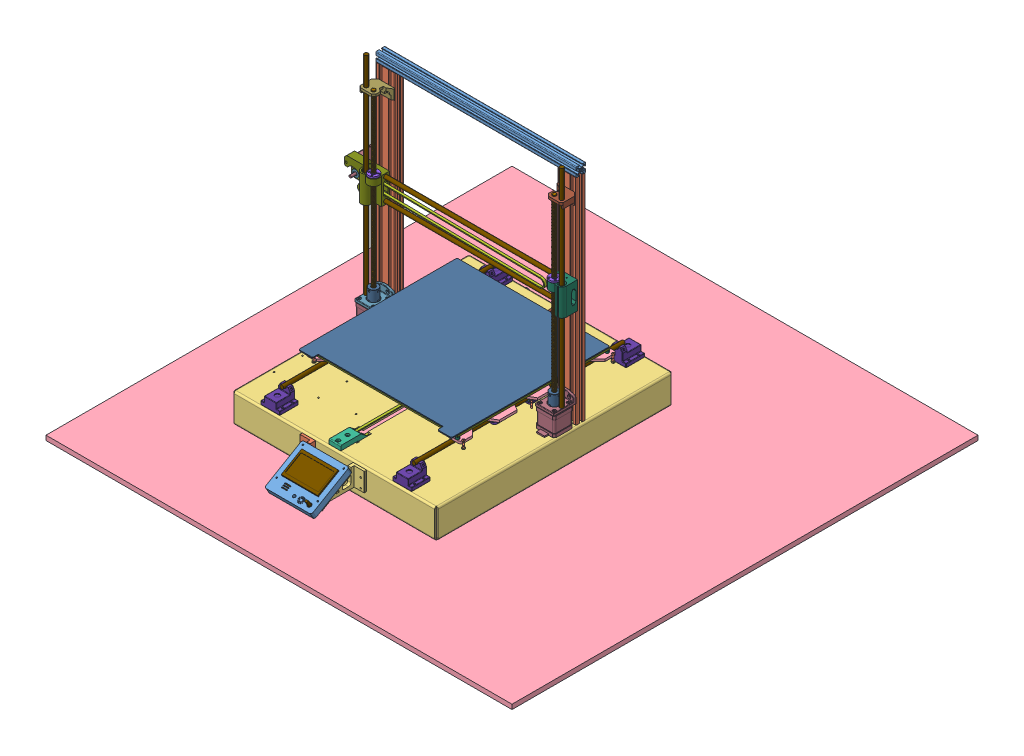
SolidWorks assembly Complete Assembly, configuration Default. Lengths in mm.
Overall size (1000 587.54 1000).
95 component instances, 40 part files, 24 mates.
Components (placement in the parent):
- Frame Assembly-1: Frame Assembly [Default] at (-40.4622 11.3616 41.4357) size (437.82 543.39 517.28)
  - Frame and Cover-1: Frame and Cover [Default] at (488.7599 -20.5544 105.3834) size (437.82 543.39 507.82)
    - TopCeiling-1: TopCeiling [20-2020-BLACK] at (-74.5195 587.4544 205.3802) x (0 0 -1) z (1 0 0) size (20 20 430)
    - UprightSides-1: UprightSides [20-2040-BLACK] at (-84.5195 117.4544 205.3802) x (1 0 0) z (0 -1 0) size (40 20 460)
    - UprightSides-2: UprightSides [20-2040-BLACK] at (-474.5195 117.4544 205.3802) x (1 0 0) z (0 -1 0) size (40 20 460)
    - printer_Cover-1: printer_Cover [Default] at (-81.1195 117.4544 131.1302) size (437.82 62.09 507.82)
    - bottom_Cover-1: bottom_Cover [Default] at (4575.451 55.3678 5402.6088) size (430 1.3 500)
  - power switch-1: power switch [Standard] at (101.2109 67.9884 116.852) size (58.2 48.75 32.65)
  - EinsyAssembly_StandOff-1: EinsyAssembly_StandOff [Default] at (-6.2482 152.6016 450.1588) x (1 0 0) z (0 -1 0) size (108.28 71 27.59)
    - Einsy_Rambo-1: Einsy_Rambo [Default] at (14.9676 86.704 68.4713) size (108.28 71 21.5)
    - standOffs-1: standOffs [Default] at (92.9775 34.4902 66.8766) x (1 0 0) z (0 -1 0) size (5 8 5)
    - standOffs-3: standOffs [Default] at (92.6031 96.0937 66.8766) x (0 1 0) z (1 0 0) size (5 8 5)
    - standOffs-4: standOffs [Default] at (-2.0225 34.4902 66.8766) x (1 0 0) z (0 -1 0) size (5 8 5)
    - standOffs-5: standOffs [Default] at (-2.0225 95.4902 66.8766) x (1 0 0) z (0 -1 0) size (5 8 5)
  - 24V15A power supply-5: 24V15A power supply [Standard] at (78.7404 93.725 345.2636) x (0 0 -1) z (0 -1 0) size (215 113 50)
  - wireClamp_25-6: wireClamp_25 [Default] at (150.0789 96.5825 393.0636) x (-1 0 0) z (0 0 1) size (41.15 12.95 25.4)
  - wireClamp_25-7: wireClamp_25 [Default] at (150.0789 96.5825 268.0636) x (-1 0 0) z (0 0 1) size (41.15 12.95 25.4)
  - wireClamp_25-8: wireClamp_25 [Default] at (169.9404 96.5825 513.6021) x (0 0 -1) z (-1 0 0) size (41.15 12.95 25.4)
  - wireClamp_25-9: wireClamp_25 [Default] at (100.0789 96.5825 168.0636) x (-1 0 0) z (0 0 1) size (41.15 12.95 25.4)
- Y Assembly-1: Y Assembly [Default] at (145.6024 117.3436 67.5916) x (0.999825 0 0.018712) z (-0.018712 0 0.999825) size (352.33 81 500.19)
  - PrintBed_328x328-1: PrintBed_328x328 [Default] at (148.0124 43.9926 305.9077) x (0.999825 0 -0.018712) z (0.018712 0 0.999825) size (328 2 340)
  - y axis motor holder-1: y axis motor holder [Default] at (-4.3973 -9.082 94.7066) x (0 1 0) z (0.999825 0 -0.018712) size (46.75 77.5 19)
  - 624U pillow-1: 624U pillow [Standard] at (74.1469 -91.082 589.2534) x (0 1 0) z (0.018712 0 0.999825) size (13 4 13)
  - 40-42 motor-1: 40-42 motor [Standard] at (-45.9053 -85.582 96.0835) x (0 1 0) z (-0.018712 0 -0.999825) size (42 64 50.7)
  - 2GT-pulley-2: 2GT-pulley [Standard] at (-58.242 121.3888 274.0832) x (0.999825 0 -0.018712) z (0.018712 0 0.999825) size (16 15 15)
  - 5mm Bed Spacer-1: 5mm Bed Spacer [Default] at (-134.2258 34.9926 494.9836) size (7 5 7)
  - 5mm Bed Spacer-2: 5mm Bed Spacer [Default] at (186.7203 34.9926 489.0988) size (7 5 7)
  - 5mm Bed Spacer-3: 5mm Bed Spacer [Default] at (180.5919 34.398 168.1573) size (7 5 7)
  - 5mm Bed Spacer-4: 5mm Bed Spacer [Default] at (-140.2301 34.398 174.1616) size (7 5 7)
  - HeatBed 300mm-1: HeatBed 300mm [Default] at (26.2199 39.9926 264.6988) x (0.999825 0 -0.018712) z (0.018712 0 0.999825) size (327 4 327)
  - Bed Holder-3: Bed Holder [Default] at (-121.7577 30.1666 403.8738) x (0.018712 0 0.999825) z (0.999825 0 -0.018712) size (22 20 30)
  - Bed Holder-4: Bed Holder [Default] at (159.7692 30.1666 322.5141) x (0.018712 0 0.999825) z (0.999825 0 -0.018712) size (22 20 30)
  - Bed Holder-5: Bed Holder [Default] at (160.7796 30.1666 376.5016) x (-0.018712 0 -0.999825) z (-0.999825 0 0.018712) size (22 20 30)
  - Bed Holder-6: Bed Holder [Default] at (-123.593 30.1666 305.8134) x (-0.018712 0 -0.999825) z (-0.999825 0 0.018712) size (22 20 30)
  - BedSlider-1: BedSlider [Default] at (160.3516 26.2711 115.9371) x (0.404254 0.914616 -0.007566) z (0.018712 0 0.999825) size (8 8 450)
  - BedSlider-2: BedSlider [Default] at (-126.0037 27.7452 121.2964) x (-0.108153 0.994132 0.002024) z (0.018712 0 0.999825) size (8 8 450)
  - lm8uu-1: lm8uu [Default] at (159.5633 20.6666 311.516) x (0.999825 0 -0.018712) z (0.018712 0 0.999825) size (15 15 24)
  - lm8uu-2: lm8uu [Default] at (160.9854 20.6666 387.4997) x (0.999825 0 -0.018712) z (0.018712 0 0.999825) size (15 15 24)
  - lm8uu-3: lm8uu [Default] at (-121.9636 20.6666 392.8757) x (0.999825 0 -0.018712) z (0.018712 0 0.999825) size (15 15 24)
  - lm8uu-4: lm8uu [Default] at (-123.3871 20.6666 316.8115) x (0.999825 0 -0.018712) z (0.018712 0 0.999825) size (15 15 24)
  - M3X16MM-1: M3X16MM [92095A184] at (190.5681 45.048 170.847) x (0.585178 0 0.810905) z (0 1 0) size (5.7 5.7 18)
  - M3X16MM-2: M3X16MM [92095A184] at (-130.3757 45.048 176.8536) x (0.988184 0 0.153271) z (0 1 0) size (5.7 5.7 18)
  - M3X16MM-3: M3X16MM [92095A184] at (-124.3691 45.048 497.7974) x (0.998383 0 0.056849) z (0 1 0) size (5.7 5.7 18)
  - M3X16MM-4: M3X16MM [92095A184] at (196.5747 45.048 491.7908) x (0.969741 0 0.244134) z (0 1 0) size (5.7 5.7 18)
  - M3-1: M3 [90591A250] at (-130.3757 17.3906 176.8536) x (0.962335 0 -0.271866) z (0 1 0) size (5.5 6.35 2.78)
  - M3-2: M3 [90591A250] at (190.5681 28.9666 170.847) x (1 0 0) z (0 1 0) size (5.5 6.35 2.78)
  - M3-3: M3 [90591A250] at (196.5747 28.9666 491.7908) x (1 0 0) z (0 1 0) size (5.5 6.35 2.78)
  - M3-4: M3 [90591A250] at (-124.3691 28.9666 497.7974) x (0.977813 0 0.209477) z (0 -1 0) size (5.5 6.35 2.78)
  - M3X16MM-5: M3X16MM [92095A184] at (170.9836 21.7666 387.3126) x (-0.990608 0 0.136731) z (0 -1 0) size (5.7 5.7 18)
  - M3X16MM-6: M3X16MM [92095A184] at (150.939 25.0666 399.5855) x (-0.757878 0 0.652397) z (0 1 0) size (5.7 5.7 18)
  - M3X16MM-7: M3X16MM [92095A184] at (150.939 25.0666 323.5885) x (-0.527844 0 0.849341) z (0 1 0) size (5.7 5.7 18)
  - M3X16MM-8: M3X16MM [92095A184] at (170.939 25.0666 323.5885) x (-0.850892 0 0.525341) z (0 1 0) size (5.7 5.7 18)
  - M3X16MM-9: M3X16MM [92095A184] at (-127.261 25.0666 399.5855) x (-0.32634 0 -0.945252) z (0 1 0) size (5.7 5.7 18)
  - M3X16MM-10: M3X16MM [92095A184] at (-107.261 25.0666 399.5855) x (-0.992075 0 0.125643) z (0 1 0) size (5.7 5.7 18)
  - M3X16MM-11: M3X16MM [92095A184] at (-127.261 25.0666 323.5885) x (-0.951434 0 -0.307853) z (0 1 0) size (5.7 5.7 18)
  - M3X16MM-12: M3X16MM [92095A184] at (-107.261 25.871 323.5885) x (-0.671818 0 -0.740717) z (0 1 0) size (5.7 5.7 18)
  - M3X16MM-13: M3X16MM [92095A184] at (5.6078 -25.582 167.032) x (-0.018712 0 -0.999825) z (0.999825 0 -0.018712) size (5.7 5.7 18)
  - M3X16MM-14: M3X16MM [92095A184] at (5.0277 5.418 136.0374) x (-0.018712 0 -0.999825) z (0.999825 0 -0.018712) size (5.7 5.7 18)
  - flatbed-2: flatbed [Default] at (144.4975 32.5796 357.2347) x (0.999825 0 -0.018712) z (0 -1 0) size (335 335 4.83)
  - y belt holder-1: y belt holder [Default] at (10.4795 30.1666 328.4691) x (0.999825 0 -0.018712) z (0 -1 0) size (14 52 33.5)
  - Y axis Idler Holder-1: Y axis Idler Holder [Default] at (21.7058 0.918 594.3056) x (0.018712 0 0.999825) z (0 -1 0) size (56.89 25 35)
  - belt-4: belt [Default] at (16.5258 -7.7421 183.9241) x (0.01871 0.016655 0.999686) z (-0.999825 0 0.018712) size (414.43 26.57 5)
- XAssembly-1: XAssembly [Default] at (346.1628 88.2378 346.754) size (485.02 523.02 93.11)
  - 40-42 motor-1: 40-42 motor [Standard] at (83.3654 18.4973 -13.9547) x (-1 0 0) z (0 0 -1) size (42 64 50.7)
  - 40-42 motor-2: 40-42 motor [Standard] at (-304.6346 18.4973 -13.9547) x (-1 0 0) z (0 0 -1) size (42 64 50.7)
  - 624U pillow-1: 624U pillow [Standard] at (-70.3846 223.0937 -25.0811) x (1 0 0) z (0 -1 0) size (13 4 13)
  - 2GT-pulley-1: 2GT-pulley [Standard] at (-298.4371 388.8614 -49.1082) x (0 0 1) z (0 1 0) size (16 15 15)
  - flanged lead screw nut-1: flanged lead screw nut [Default] at (-380.1347 299.5237 42.4453) x (-0.892252 0 0.451538) z (0 -1 0) size (22 22 19.88)
  - flanged lead screw nut-2: flanged lead screw nut [Default] at (7.8652 299.5237 42.4453) x (0.837169 0 0.546944) z (0 -1 0) size (22 22 19.88)
  - 40-42 motor-3: 40-42 motor [Standard] at (-354.4079 323.9237 -22.4949) x (-1 0 0) z (0 1 0) size (42 64 50.7)
  - BedSlider-1: BedSlider [Default] at (-396.8878 512.0237 35.3611) x (0.113678 0 -0.993518) z (0 -1 0) size (8 8 450)
  - BedSlider-2: BedSlider [Default] at (19.3272 512.0237 36.7178) x (-0.378404 0 -0.925641) z (0 -1 0) size (8 8 450)
  - Z threaded rod-1: Z threaded rod [Standard] at (-380.1346 84.0237 42.4453) x (0 0 -1) z (0 1 0) size (8.01 8.01 375.98)
  - Z threaded rod-2: Z threaded rod [Standard] at (7.8394 454.0237 42.4545) x (-1 0 0) z (0 -1 0) size (8.01 8.01 375.98)
  - Z coupler-1: Z coupler [Standard] at (-380.1346 75.0237 42.4453) size (20 26 20)
  - Z coupler-2: Z coupler [Standard] at (7.8654 75.0237 42.4453) size (20 26 20)
  - ztop holder Right-1: ztop holder Right [Default] at (-30.6346 447.0237 42.4453) x (-1 0 0) z (0 0 -1) size (43 21 35.75)
  - ztop holder Left-1: ztop holder Left [Default] at (-380.1346 447.0237 42.4453) x (-1 0 0) z (0 0 -1) size (43 21 35.75)
  - Y motor holder right-1: Y motor holder right [Default] at (7.8654 60.0237 42.4453) size (39.5 20 48)
  - Y motor holder left-1: Y motor holder left [Default] at (-380.1346 60.0237 42.4453) size (39.5 20 48)
  - Right z holder-1: Right z holder [Default] at (15.6154 267.0237 18.9453) x (0 1 0) z (1 0 0) size (58 34.5 38.04)
  - Motor Mount-2: Motor Mount [Default] at (-369.4576 296.0237 35.9453) x (-1 0 0) z (0 0 -1) size (81.27 58 36)
  - BedSlider-3: BedSlider [Default] at (33.1119 291.8257 20.521) x (0 0 -1) z (-1 0 0) size (8 8 450)
  - BedSlider-4: BedSlider [Default] at (-420.7175 244.9609 20.2907) x (0 0.24335 -0.969938) z (1 0 0) size (8 8 450)
  - belt-1: belt [Default] at (-397.4115 269.2854 25.1733) size (414.43 26.57 5)
- Linear Holder-1: Linear Holder [Default] at (17.2782 112.2616 642.1993) x (1 0 0) z (0 0 -1) size (41 31.25 40)
- Linear Holder-2: Linear Holder [Default] at (300.2782 112.2616 642.1993) x (1 0 0) z (0 0 -1) size (41 31.25 40)
- Linear Holder-3: Linear Holder [Default] at (300.2782 112.2616 182.1993) x (-1 0 0) z (0 0 1) size (41 31.25 40)
- Linear Holder-4: Linear Holder [Default] at (17.2782 112.2616 182.1993) x (-1 0 0) z (0 0 1) size (41 31.25 40)
- Screen Assembly-1: Screen Assembly [Default] at (221.4776 20.2859 772.4029) x (1 0 0) z (0 0.863792 0.503849) size (138.95 107.39 82.56)
  - Full Graphic Smart Controller-2: Full Graphic Smart Controller [Default] at (-62.6096 73.8061 19.9222) size (102.9 86.75 34.7)
  - LCD_Case-2: LCD_Case [Default] at (-68.3227 84.8365 18.8222) size (100.75 94 14)
  - LCD_Holder_Left-1: LCD_Holder_Left [Default] at (-103.0846 92.3537 17.2607) x (1 0 0) z (0 -0.863792 0.503849) size (29 50.29 77.65)
  - LCD_Holder_Right-1: LCD_Holder_Right [Default] at (-15.1346 92.3537 17.2607) x (1 0 0) z (0 -0.863792 0.503849) size (29 50.29 77.65)
- floor-1: floor [Default] at (-88.7745 23.3717 -25.9365) size (1000 10 1000)
Mates (geometry in assembly coordinates):
- Coincident1: coincident anti-aligned: plane of Frame Assembly-1/Frame and Cover-1/printer_Cover-1 through (367.1782 108.2616 277.9493) normal (0 1 0); plane of XAssembly-1/40-42 motor-1 through (375.0282 108.2616 418.8993) normal (0 -1 0)
- Coincident2: coincident anti-aligned: plane of Frame Assembly-1/Frame and Cover-1/UprightSides-1 through (360.6402 568.2616 362.1993) normal (0 0 1); plane of XAssembly-1/Y motor holder right-1 through (354.0282 148.2616 362.1993) normal (0 0 -1)
- Coincident3: coincident aligned: plane of Frame Assembly-1/Frame and Cover-1/UprightSides-1 through (373.7782 568.2616 355.3373) normal (1 0 0); plane of XAssembly-1/Y motor holder right-1 through (373.7782 154.2616 368.1993) normal (1 0 0)
- Coincident23: coincident anti-aligned: plane of Frame Assembly-1/Frame and Cover-1/printer_Cover-1 through (367.1782 108.2616 277.9493) normal (0 1 0); plane of Y Assembly-1/y axis motor holder-1 through (158.4337 108.2616 198.1993) normal (0 -1 0)
- Coincident11: coincident: line of Frame Assembly-1/Frame and Cover-1/printer_Cover-1 through (373.7782 108.2616 162.1993) axis (-1 0 0); plane of Y Assembly-1/y axis motor holder-1 through (158.4337 108.2616 162.1993) normal (0 0 -1)
- Coincident14: coincident anti-aligned: plane of Frame Assembly-1/Frame and Cover-1/printer_Cover-1 through (367.1782 108.2616 277.9493) normal (0 1 0); plane of Linear Holder-1 through (-3.2218 108.2616 622.1993) normal (0 -1 0)
- Coincident15: coincident anti-aligned: plane of Frame Assembly-1/Frame and Cover-1/printer_Cover-1 through (367.1782 108.2616 277.9493) normal (0 1 0); plane of Linear Holder-2 through (279.7782 108.2616 622.1993) normal (0 -1 0)
- Coincident16: coincident anti-aligned: plane of Frame Assembly-1/Frame and Cover-1/printer_Cover-1 through (367.1782 108.2616 277.9493) normal (0 1 0); plane of Linear Holder-3 through (320.7782 108.2616 202.1993) normal (0 -1 0)
- Coincident17: coincident anti-aligned: plane of Frame Assembly-1/Frame and Cover-1/printer_Cover-1 through (367.1782 108.2616 277.9493) normal (0 1 0); plane of Linear Holder-4 through (37.7782 108.2616 202.1993) normal (0 -1 0)
- Coincident18: coincident: line of Frame Assembly-1/Frame and Cover-1/printer_Cover-1 through (373.7782 108.2616 162.1993) axis (-1 0 0); plane of Linear Holder-4 through (17.2782 112.2616 162.1993) normal (0 0 -1)
- Coincident19: coincident: line of Frame Assembly-1/Frame and Cover-1/printer_Cover-1 through (373.7782 108.2616 162.1993) axis (-1 0 0); plane of Linear Holder-3 through (300.2782 112.2616 162.1993) normal (0 0 -1)
- Coincident20: coincident: line of Frame Assembly-1/Frame and Cover-1/printer_Cover-1 through (-56.2218 108.2616 662.1993) axis (1 0 0); plane of Linear Holder-1 through (17.2782 112.2616 662.1993) normal (0 0 1)
- Coincident21: coincident: line of Frame Assembly-1/Frame and Cover-1/printer_Cover-1 through (-56.2218 108.2616 662.1993) axis (1 0 0); plane of Linear Holder-2 through (300.2782 112.2616 662.1993) normal (0 0 1)
- Distance2: distance = 53 mm: plane of Linear Holder-1 through (-3.2218 116.2616 622.1993) normal (-1 0 0); line of Frame Assembly-1/Frame and Cover-1/printer_Cover-1 through (-56.2218 108.2616 162.1993) axis (0 0 1)
- Distance3: distance = 53 mm: plane of Linear Holder-2 through (320.7782 116.2616 622.1993) normal (1 0 0); line of Frame Assembly-1/Frame and Cover-1/printer_Cover-1 through (373.7782 108.2616 662.1993) axis (0 0 -1)
- Distance4: distance = 53 mm: plane of Linear Holder-4 through (-3.2218 116.2616 202.1993) normal (-1 0 0); line of Frame Assembly-1/Frame and Cover-1/printer_Cover-1 through (-56.2218 108.2616 162.1993) axis (0 0 1)
- Distance5: distance = 53 mm: plane of Linear Holder-3 through (320.7782 116.2616 202.1993) normal (1 0 0); line of Frame Assembly-1/Frame and Cover-1/printer_Cover-1 through (373.7782 108.2616 662.1993) axis (0 0 -1)
- Coincident24: coincident anti-aligned: plane of Frame Assembly-1/Frame and Cover-1/printer_Cover-1 through (367.1782 108.2616 666.1109) normal (0 0 1); plane of ? through (198.7782 54.3355 666.1109) normal (0 0 -1)
- Coincident25: coincident anti-aligned: line of Frame Assembly-1/Frame and Cover-1/printer_Cover-1 through (-56.2513 104.35 666.1109) axis (1 0 0); line of ? through (225.7782 104.35 666.1109) axis (-1 0 0)
- Distance6: distance = 146 mm: line of ? through (227.7782 102.35 666.1109) axis (0 -1 0); line of Frame Assembly-1/Frame and Cover-1/printer_Cover-1 through (373.7782 108.2616 662.1993) axis (0 0 -1)
- Coincident26: coincident anti-aligned: plane of Frame Assembly-1/Frame and Cover-1/printer_Cover-1 through (367.1782 108.2616 666.1109) normal (0 0 1); plane of Screen Assembly-1/LCD_Holder_Right-1 through (199.343 64.35 666.1109) normal (0 0 -1)
- Coincident29: coincident aligned: line of Frame Assembly-1/Frame and Cover-1/printer_Cover-1 through (-56.2513 104.35 666.1109) axis (1 0 0); line of Screen Assembly-1/LCD_Holder_Left-1 through (90.393 104.35 666.1109) axis (1 0 0)
- Coincident31: coincident anti-aligned: plane of ? through (363.7664 38.475 572.3278) normal (0 -1 0); plane of floor-1 through (-88.8804 38.475 -25.5939) normal (0 1 0)
- Distance7: distance = 146.55 mm: line of Screen Assembly-1/LCD_Holder_Right-1 through (227.343 64.35 671.1109) axis (0 1 0); line of Frame Assembly-1/Frame and Cover-1/printer_Cover-1 through (373.8077 50.0866 666.1109) axis (0 1 0)
